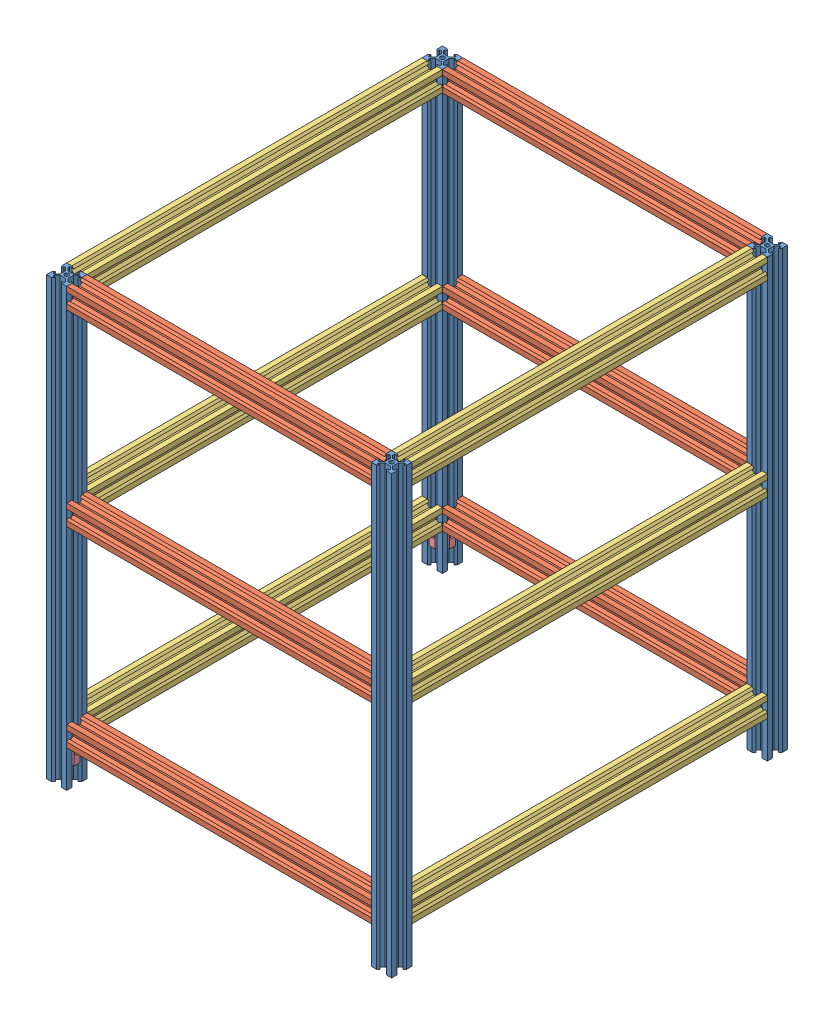
SolidWorks assembly singal, configuration 默认. Lengths in mm.
Overall size (340 430 390).
20 component instances, 4 part files, 55 mates.
Components (placement in the parent):
- 2020lv_430-1: 2020lv_430 [默认] at (-104.4028 -206.392 400) size (20 430 20)
- 2020lv_430-2: 2020lv_430 [默认] at (215.5972 -206.392 30) size (20 430 20)
- 2020lv_430-3: 2020lv_430 [默认] at (-104.4028 -206.392 30) size (20 430 20)
- 2020lv_430-4: 2020lv_430 [默认] at (215.5972 -206.392 400) size (20 430 20)
- 2020lv_300-1: 2020lv_300 [默认] at (205.5972 -160.1212 400) x (0 1 0) z (0 0 1) size (20 300 20)
- 2020lv_350-1: 2020lv_350 [默认] at (-104.4028 -160.1212 40) x (-1 0 0) z (0 1 0) size (20 350 20)
- 2020lv_300-2: 2020lv_300 [默认] at (205.5972 -160.1212 30) x (0 1 0) z (0 0 1) size (20 300 20)
- 2020lv_350-3: 2020lv_350 [默认] at (215.5972 -160.1212 40) x (-1 0 0) z (0 1 0) size (20 350 20)
- 2020jiaocao-1: 2020jiaocao [默认] at (-104.5028 -167.1212 40) x (0 -1 0) z (-1 0 0) size (25 26 10)
- 2020jiaocao-2: 2020jiaocao [默认] at (-104.5028 -167.1212 390) x (0 -1 0) z (1 0 0) size (25 26 10)
- 2020jiaocao-3: 2020jiaocao [默认] at (-94.4028 -167.1212 29.9) x (0 -1 0) z (0 0 1) size (25 26 10)
- 2020jiaocao-4: 2020jiaocao [默认] at (-94.4028 -167.1212 399.9) x (0 -1 0) z (0 0 1) size (25 26 10)
- 2020lv_300-3: 2020lv_300 [默认] at (205.5972 28.6724 400) x (0 1 0) z (0 0 1) size (20 300 20)
- 2020lv_300-4: 2020lv_300 [默认] at (205.5972 28.6724 30) x (0 1 0) z (0 0 1) size (20 300 20)
- 2020lv_350-4: 2020lv_350 [默认] at (215.5972 28.6724 40) x (-1 0 0) z (0 1 0) size (20 350 20)
- 2020lv_350-5: 2020lv_350 [默认] at (-104.4028 28.6724 40) x (-1 0 0) z (0 1 0) size (20 350 20)
- 2020lv_350-6: 2020lv_350 [默认] at (215.5972 213.608 40) x (-1 0 0) z (0 1 0) size (20 350 20)
- 2020lv_350-7: 2020lv_350 [默认] at (-104.4028 213.608 40) x (-1 0 0) z (0 1 0) size (20 350 20)
- 2020lv_300-5: 2020lv_300 [默认] at (205.5972 213.608 30) x (0 1 0) z (0 0 1) size (20 300 20)
- 2020lv_300-6: 2020lv_300 [默认] at (205.5972 213.608 400) x (0 1 0) z (0 0 1) size (20 300 20)
Mates (geometry in assembly coordinates):
- 重合1: coincident aligned: plane of 2020lv_400-1 through (-104.4028 -206.392 400) normal (0 -1 0); plane of 2020lv_400-3 through (-104.4028 -206.392 30) normal (0 -1 0)
- 重合2: coincident aligned: plane of 2020lv_400-3 through (-104.4028 -206.392 30) normal (0 -1 0); plane of 2020lv_400-4 through (215.5972 -206.392 400) normal (0 -1 0)
- 重合3: coincident aligned: plane of 2020lv_400-2 through (215.5972 -206.392 30) normal (0 -1 0); plane of 2020lv_400-4 through (215.5972 -206.392 400) normal (0 -1 0)
- 重合4: coincident aligned: plane of 2020lv_400-1 through (-94.4028 223.608 410) normal (0 0 1); plane of 2020lv_400-4 through (225.5972 223.608 410) normal (0 0 1)
- 重合5: coincident aligned: plane of 2020lv_400-2 through (225.5972 223.608 40) normal (1 0 0); plane of 2020lv_400-4 through (225.5972 223.608 390) normal (1 0 0)
- 重合6: coincident aligned: plane of 2020lv_400-2 through (205.5972 223.608 20) normal (0 0 -1); plane of 2020lv_400-3 through (-114.4028 223.608 20) normal (0 0 -1)
- 重合7: coincident aligned: plane of 2020lv_400-1 through (-114.4028 223.608 410) normal (-1 0 0); plane of 2020lv_400-3 through (-114.4028 223.608 40) normal (-1 0 0)
- 重合8: coincident aligned: plane of 2020lv_400-1 through (-94.4028 223.608 410) normal (0 0 1); plane of 2020lv_300-1 through (-94.4028 -150.1212 410) normal (0 0 1)
- 重合9: coincident anti-aligned: plane of 2020lv_400-1 through (-94.4028 223.608 410) normal (1 0 0); plane of 2020lv_300-1 through (-94.4028 -160.1212 400) normal (-1 0 0)
- 重合10: coincident anti-aligned: plane of 2020lv_400-4 through (205.5972 223.608 390) normal (-1 0 0); plane of 2020lv_300-1 through (205.5972 -160.1212 400) normal (1 0 0)
- 重合12: coincident aligned: plane of 2020lv_300-1 through (-94.4028 -150.1212 390) normal (0 1 0); plane of 2020lv_350-1 through (-114.4028 -150.1212 390) normal (0 1 0)
- 重合13: coincident anti-aligned: plane of 2020lv_400-1 through (-94.4028 223.608 390) normal (0 0 -1); plane of 2020lv_350-1 through (-104.4028 -160.1212 390) normal (0 0 1)
- 重合14: coincident aligned: plane of 2020lv_400-1 through (-114.4028 223.608 390) normal (-1 0 0); plane of 2020lv_350-1 through (-114.4028 -150.1212 390) normal (-1 0 0)
- 重合15: coincident anti-aligned: plane of 2020lv_400-3 through (-114.4028 223.608 40) normal (0 0 1); plane of 2020lv_350-1 through (-104.4028 -160.1212 40) normal (0 0 -1)
- 重合16: coincident aligned: plane of 2020lv_400-3 through (-114.4028 223.608 40) normal (0 0 1); plane of 2020lv_300-2 through (-94.4028 -150.1212 40) normal (0 0 1)
- 重合17: coincident aligned: plane of 2020lv_350-1 through (-94.4028 -150.1212 390) normal (0 1 0); plane of 2020lv_300-2 through (-94.4028 -150.1212 40) normal (0 1 0)
- 重合18: coincident anti-aligned: plane of 2020lv_400-3 through (-94.4028 223.608 40) normal (1 0 0); plane of 2020lv_300-2 through (-94.4028 -160.1212 30) normal (-1 0 0)
- 重合19: coincident aligned: plane of 2020lv_300-1 through (-94.4028 -150.1212 390) normal (0 1 0); plane of 2020lv_350-3 through (205.5972 -150.1212 390) normal (0 1 0)
- 重合20: coincident anti-aligned: plane of 2020lv_400-4 through (205.5972 223.608 390) normal (0 0 -1); plane of 2020lv_350-3 through (215.5972 -160.1212 390) normal (0 0 1)
- 重合21: coincident aligned: plane of 2020lv_400-2 through (225.5972 223.608 20) normal (1 0 0); plane of 2020lv_350-3 through (225.5972 -150.1212 390) normal (1 0 0)
- 重合22: coincident aligned: plane of 2020lv_400-3 through (-94.4028 223.608 40) normal (0 0 1); plane of 2020jiaocao-1 through (-107.5028 -189.1212 40) normal (0 0 1)
- 重合23: coincident: line of 2020lv_400-3 through (-107.5028 223.608 38.2) axis (0 -1 0); plane of 2020jiaocao-1 through (-107.5028 -168.3212 60) normal (-1 0 0)
- 重合24: coincident aligned: plane of 2020lv_350-1 through (-94.4028 -170.1212 390) normal (0 -1 0); plane of 2020jiaocao-1 through (-107.5028 -170.1212 60) normal (0 -1 0)
- 重合25: coincident aligned: plane of 2020jiaocao-1 through (-107.5028 -168.3212 60) normal (-1 0 0); plane of 2020jiaocao-2 through (-107.5028 -168.3212 370) normal (-1 0 0)
- 重合26: coincident aligned: plane of 2020lv_400-1 through (-94.4028 223.608 390) normal (0 0 -1); plane of 2020jiaocao-2 through (-101.5028 -189.1212 390) normal (0 0 -1)
- 重合27: coincident aligned: plane of 2020lv_350-1 through (-114.4028 -170.1212 390) normal (0 -1 0); plane of 2020jiaocao-2 through (-101.5028 -170.1212 370) normal (0 -1 0)
- 重合28: coincident aligned: plane of 2020lv_400-3 through (-94.4028 223.608 40) normal (1 0 0); plane of 2020jiaocao-3 through (-94.4028 -189.1212 32.9) normal (1 0 0)
- 重合29: coincident aligned: plane of 2020lv_300-2 through (-94.4028 -170.1212 20) normal (0 -1 0); plane of 2020jiaocao-3 through (-74.4028 -170.1212 32.9) normal (0 -1 0)
- 重合30: coincident: line of 2020lv_400-3 through (-96.2028 223.608 26.9) axis (0 -1 0); plane of 2020jiaocao-3 through (-74.4028 -168.3212 26.9) normal (0 0 -1)
- 重合31: coincident aligned: plane of 2020lv_400-1 through (-94.4028 223.608 410) normal (1 0 0); plane of 2020jiaocao-4 through (-94.4028 -189.1212 402.9) normal (1 0 0)
- 重合32: coincident aligned: plane of 2020lv_300-1 through (-94.4028 -170.1212 390) normal (0 -1 0); plane of 2020jiaocao-4 through (-74.4028 -170.1212 402.9) normal (0 -1 0)
- 重合33: coincident: line of 2020lv_300-1 through (-94.4028 -168.3212 396.9) axis (1 0 0); plane of 2020jiaocao-4 through (-74.4028 -168.3212 396.9) normal (0 0 -1)
- 重合35: coincident aligned: plane of 2020lv_300-1 through (-94.4028 -150.1212 410) normal (0 0 1); plane of 2020lv_300-3 through (-94.4028 38.6724 410) normal (0 0 1)
- 重合36: coincident anti-aligned: plane of 2020lv_400-4 through (205.5972 223.608 390) normal (-1 0 0); plane of 2020lv_300-3 through (205.5972 28.6724 400) normal (1 0 0)
- 重合37: coincident aligned: plane of 2020lv_300-3 through (-94.4028 38.6724 390) normal (0 1 0); plane of 2020lv_300-4 through (-94.4028 38.6724 40) normal (0 1 0)
- 重合38: coincident aligned: plane of 2020lv_400-2 through (205.5972 223.608 40) normal (0 0 1); plane of 2020lv_300-4 through (-94.4028 38.6724 40) normal (0 0 1)
- 重合39: coincident anti-aligned: plane of 2020lv_400-3 through (-94.4028 223.608 20) normal (1 0 0); plane of 2020lv_300-4 through (-94.4028 28.6724 30) normal (-1 0 0)
- 重合40: coincident anti-aligned: plane of 2020lv_400-4 through (205.5972 223.608 390) normal (0 0 -1); plane of 2020lv_350-4 through (215.5972 28.6724 390) normal (0 0 1)
- 重合41: coincident aligned: plane of 2020lv_300-3 through (-94.4028 38.6724 390) normal (0 1 0); plane of 2020lv_350-4 through (205.5972 38.6724 390) normal (0 1 0)
- 重合42: coincident aligned: plane of 2020lv_400-4 through (225.5972 223.608 390) normal (1 0 0); plane of 2020lv_350-4 through (225.5972 38.6724 390) normal (1 0 0)
- 重合44: coincident aligned: plane of 2020lv_300-3 through (-94.4028 38.6724 390) normal (0 1 0); plane of 2020lv_350-5 through (-94.4028 38.6724 390) normal (0 1 0)
- 重合45: coincident anti-aligned: plane of 2020lv_300-3 through (-94.4028 18.6724 390) normal (0 0 -1); plane of 2020lv_350-5 through (-104.4028 28.6724 390) normal (0 0 1)
- 重合46: coincident aligned: plane of 2020lv_400-1 through (-114.4028 223.608 410) normal (-1 0 0); plane of 2020lv_350-5 through (-114.4028 38.6724 390) normal (-1 0 0)
- 重合48: coincident aligned: plane of 2020lv_400-4 through (225.5972 223.608 390) normal (1 0 0); plane of 2020lv_350-6 through (225.5972 223.608 390) normal (1 0 0)
- 重合49: coincident anti-aligned: plane of 2020lv_400-2 through (205.5972 223.608 40) normal (0 0 1); plane of 2020lv_350-6 through (215.5972 213.608 40) normal (0 0 -1)
- 重合50: coincident anti-aligned: plane of 2020lv_400-3 through (-114.4028 223.608 40) normal (0 0 1); plane of 2020lv_350-7 through (-104.4028 213.608 40) normal (0 0 -1)
- 重合51: coincident aligned: plane of 2020lv_400-3 through (-114.4028 223.608 20) normal (-1 0 0); plane of 2020lv_350-7 through (-114.4028 223.608 390) normal (-1 0 0)
- 重合52: coincident aligned: plane of 2020lv_350-6 through (225.5972 223.608 390) normal (0 1 0); plane of 2020lv_350-7 through (-94.4028 223.608 390) normal (0 1 0)
- 重合53: coincident aligned: plane of 2020lv_350-7 through (-114.4028 223.608 390) normal (0 1 0); plane of 2020lv_300-5 through (-94.4028 223.608 40) normal (0 1 0)
- 重合54: coincident anti-aligned: plane of 2020lv_400-2 through (205.5972 223.608 40) normal (-1 0 0); plane of 2020lv_300-5 through (205.5972 213.608 30) normal (1 0 0)
- 重合55: coincident aligned: plane of 2020lv_400-2 through (205.5972 223.608 20) normal (0 0 -1); plane of 2020lv_300-5 through (-94.4028 223.608 20) normal (0 0 -1)
- 重合56: coincident aligned: plane of 2020lv_350-6 through (205.5972 223.608 390) normal (0 1 0); plane of 2020lv_300-6 through (-94.4028 223.608 390) normal (0 1 0)
- 重合57: coincident anti-aligned: plane of 2020lv_400-1 through (-94.4028 223.608 390) normal (1 0 0); plane of 2020lv_300-6 through (-94.4028 213.608 400) normal (-1 0 0)
- 重合58: coincident aligned: plane of 2020lv_400-1 through (-94.4028 223.608 410) normal (0 0 1); plane of 2020lv_300-6 through (-94.4028 223.608 410) normal (0 0 1)
- 重合59: coincident aligned: plane of 2020lv_430-2 through (215.5972 223.608 30) normal (0 1 0); plane of 2020lv_350-6 through (225.5972 223.608 390) normal (0 1 0)
